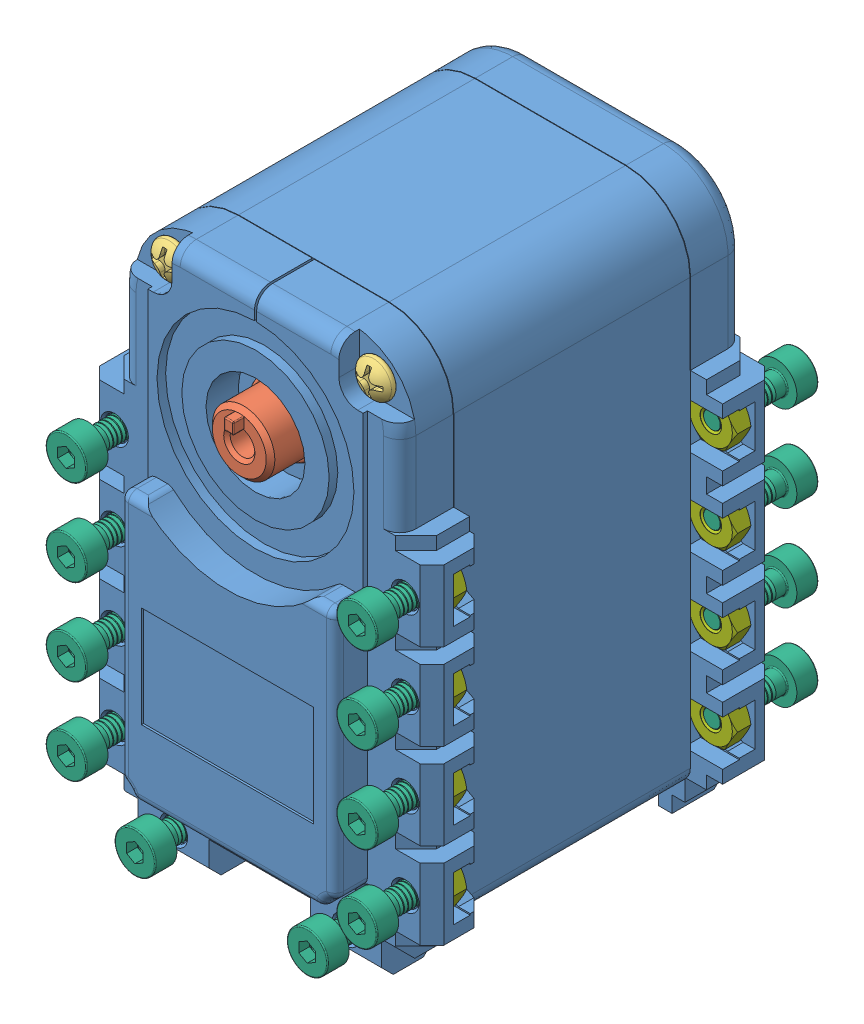
SolidWorks assembly AX-18F, configuration Défaut. Lengths in mm.
Overall size (32 50.04 41).
49 component instances, 7 part files, 18 mates.
Components (placement in the parent):
- ASSY_DUMMY___-1: ASSY_DUMMY___ [Défaut] at origin size (32 50.04 38.37)
- ASSY_GEAR-WHEEL___DUMMY-1: ASSY_GEAR-WHEEL___DUMMY [Défaut] at (0 0 -2) x (-1 0 0) z (0 0 1) size (6.5 6.5 5.51)
- DX124_SCREW-COVER___-1: DX124_SCREW-COVER___ [Défaut] at (9.5 8.5 14.5) x (-1 0 0) z (0 1 0) size (3.5 30.7 3.5)
- DX124_SCREW-COVER___-2: DX124_SCREW-COVER___ [Défaut] at (-9.5 8.5 14.5) x (-1 0 0) z (0 1 0) size (3.5 30.7 3.5)
- DX124_SCREW-COVER___-3: DX124_SCREW-COVER___ [Défaut] at (10.5 -33 14.5) x (-1 0 0) z (0 1 0) size (3.5 30.7 3.5)
- DX124_SCREW-COVER___-4: DX124_SCREW-COVER___ [Défaut] at (-10.5 -33 14.5) x (-1 0 0) z (0 1 0) size (3.5 30.7 3.5)
- 099990987____-1: 099990987____ [Défaut] at (5.05 -15.19 -9.75) x (1 0 0) z (0 1 0) size (9.9 9.43 4.9)
- 099990987____-2: 099990987____ [Défaut] at (-4.95 -15.19 -9.75) x (1 0 0) z (0 1 0) size (9.9 9.43 4.9)
- DC04_B01_INSERT_M3-1: DC04_B01_INSERT_M3 [Défaut] at (0 0 -18.4) x (-1 0 0) z (0 1 0) size (4.98 7 4.98)
- socket head cap screw_iso-1: socket head cap screw_iso [ISO 4762 M2 x 6 --- 6S] at (-13.5 -6.5 20.5) x (0 0 -1) z (1 0 0) size (8 3.8 3.8)
- hex nut style 1 gradeab_iso-1: hex nut style 1 gradeab_iso [Hexagon Nut ISO - 4032 - M2 - D - S] at (-13.5 -6.5 14) x (0 1 0) z (0 0 1) size (4 4.62 1.6)
- hex nut style 1 gradeab_iso-2: hex nut style 1 gradeab_iso [Hexagon Nut ISO - 4032 - M2 - D - S] at (-13.5 -14.5 14) x (0 1 0) z (0 0 1) size (4 4.62 1.6)
- hex nut style 1 gradeab_iso-3: hex nut style 1 gradeab_iso [Hexagon Nut ISO - 4032 - M2 - D - S] at (-13.5 -22.5 14) x (0 1 0) z (0 0 1) size (4 4.62 1.6)
- socket head cap screw_iso-2: socket head cap screw_iso [ISO 4762 M2 x 6 --- 6S] at (-13.5 -14.5 20.5) x (0 0 -1) z (1 0 0) size (8 3.8 3.8)
- socket head cap screw_iso-3: socket head cap screw_iso [ISO 4762 M2 x 6 --- 6S] at (-13.5 -22.5 20.5) x (0 0 -1) z (1 0 0) size (8 3.8 3.8)
- socket head cap screw_iso-4: socket head cap screw_iso [ISO 4762 M2 x 6 --- 6S] at (-13.5 -30.5 20.5) x (0 0 -1) z (1 0 0) size (8 3.8 3.8)
- hex nut style 1 gradeab_iso-4: hex nut style 1 gradeab_iso [Hexagon Nut ISO - 4032 - M2 - D - S] at (-13.5 -30.5 14) x (0 1 0) z (0 0 1) size (4 4.62 1.6)
- hex nut style 1 gradeab_iso-5: hex nut style 1 gradeab_iso [Hexagon Nut ISO - 4032 - M2 - D - S] at (13.5 -6.5 12.4001) x (0 1 0) z (0 0 -1) size (4 4.62 1.6)
- socket head cap screw_iso-5: socket head cap screw_iso [ISO 4762 M2 x 6 --- 6S] at (13.5 -6.5 20.5) x (0 0 -1) z (1 0 0) size (8 3.8 3.8)
- hex nut style 1 gradeab_iso-6: hex nut style 1 gradeab_iso [Hexagon Nut ISO - 4032 - M2 - D - S] at (13.5 -14.5 12.4001) x (0 1 0) z (0 0 -1) size (4 4.62 1.6)
- hex nut style 1 gradeab_iso-7: hex nut style 1 gradeab_iso [Hexagon Nut ISO - 4032 - M2 - D - S] at (13.5 -22.5 12.4001) x (0 1 0) z (0 0 -1) size (4 4.62 1.6)
- socket head cap screw_iso-6: socket head cap screw_iso [ISO 4762 M2 x 6 --- 6S] at (13.5 -14.5 20.5) x (0 0 -1) z (1 0 0) size (8 3.8 3.8)
- socket head cap screw_iso-7: socket head cap screw_iso [ISO 4762 M2 x 6 --- 6S] at (13.5 -22.5 20.5) x (0 0 -1) z (1 0 0) size (8 3.8 3.8)
- socket head cap screw_iso-8: socket head cap screw_iso [ISO 4762 M2 x 6 --- 6S] at (13.5 -30.5 20.5) x (0 0 -1) z (1 0 0) size (8 3.8 3.8)
- hex nut style 1 gradeab_iso-8: hex nut style 1 gradeab_iso [Hexagon Nut ISO - 4032 - M2 - D - S] at (13.5 -30.5 12.4001) x (0 1 0) z (0 0 -1) size (4 4.62 1.6)
- socket head cap screw_iso-9: socket head cap screw_iso [ISO 4762 M2 x 6 --- 6S] at (-13.5 -6.5 -20.5) x (0 0 1) z (-1 0 0) size (8 3.8 3.8)
- hex nut style 1 gradeab_iso-9: hex nut style 1 gradeab_iso [Hexagon Nut ISO - 4032 - M2 - D - S] at (-13.5 -6.5 -12.4001) x (0 1 0) z (0 0 1) size (4 4.62 1.6)
- hex nut style 1 gradeab_iso-10: hex nut style 1 gradeab_iso [Hexagon Nut ISO - 4032 - M2 - D - S] at (-13.5 -14.5 -12.4001) x (0 1 0) z (0 0 1) size (4 4.62 1.6)
- hex nut style 1 gradeab_iso-11: hex nut style 1 gradeab_iso [Hexagon Nut ISO - 4032 - M2 - D - S] at (-13.5 -22.5 -12.4001) x (0 1 0) z (0 0 1) size (4 4.62 1.6)
- socket head cap screw_iso-10: socket head cap screw_iso [ISO 4762 M2 x 6 --- 6S] at (-13.5 -14.5 -20.5) x (0 0 1) z (-1 0 0) size (8 3.8 3.8)
- socket head cap screw_iso-11: socket head cap screw_iso [ISO 4762 M2 x 6 --- 6S] at (-13.5 -22.5 -20.5) x (0 0 1) z (-1 0 0) size (8 3.8 3.8)
- socket head cap screw_iso-12: socket head cap screw_iso [ISO 4762 M2 x 6 --- 6S] at (-13.5 -30.5 -20.5) x (0 0 1) z (-1 0 0) size (8 3.8 3.8)
- hex nut style 1 gradeab_iso-12: hex nut style 1 gradeab_iso [Hexagon Nut ISO - 4032 - M2 - D - S] at (-13.5 -30.5 -12.4001) x (0 1 0) z (0 0 1) size (4 4.62 1.6)
- hex nut style 1 gradeab_iso-13: hex nut style 1 gradeab_iso [Hexagon Nut ISO - 4032 - M2 - D - S] at (13.5 -6.5 -14) x (0 1 0) z (0 0 -1) size (4 4.62 1.6)
- socket head cap screw_iso-13: socket head cap screw_iso [ISO 4762 M2 x 6 --- 6S] at (13.5 -6.5 -20.5) x (0 0 1) z (-1 0 0) size (8 3.8 3.8)
- hex nut style 1 gradeab_iso-14: hex nut style 1 gradeab_iso [Hexagon Nut ISO - 4032 - M2 - D - S] at (13.5 -14.5 -14) x (0 1 0) z (0 0 -1) size (4 4.62 1.6)
- hex nut style 1 gradeab_iso-15: hex nut style 1 gradeab_iso [Hexagon Nut ISO - 4032 - M2 - D - S] at (13.5 -22.5 -14) x (0 1 0) z (0 0 -1) size (4 4.62 1.6)
- socket head cap screw_iso-14: socket head cap screw_iso [ISO 4762 M2 x 6 --- 6S] at (13.5 -14.5 -20.5) x (0 0 1) z (-1 0 0) size (8 3.8 3.8)
- socket head cap screw_iso-15: socket head cap screw_iso [ISO 4762 M2 x 6 --- 6S] at (13.5 -22.5 -20.5) x (0 0 1) z (-1 0 0) size (8 3.8 3.8)
- socket head cap screw_iso-16: socket head cap screw_iso [ISO 4762 M2 x 6 --- 6S] at (13.5 -30.5 -20.5) x (0 0 1) z (-1 0 0) size (8 3.8 3.8)
- hex nut style 1 gradeab_iso-16: hex nut style 1 gradeab_iso [Hexagon Nut ISO - 4032 - M2 - D - S] at (13.5 -30.5 -14) x (0 1 0) z (0 0 -1) size (4 4.62 1.6)
- socket head cap screw_iso-17: socket head cap screw_iso [ISO 4762 M2 x 5 --- 5S] at (-8 -36 19.6) x (0 0 -1) z (1 0 0) size (7 3.8 3.8)
- hex nut style 1 gradeab_iso-17: hex nut style 1 gradeab_iso [Hexagon Nut ISO - 4032 - M2 - D - S] at (-8 -36 14) x (-1 0 0) z (0 0 1) size (4 4.62 1.6)
- hex nut style 1 gradeab_iso-18: hex nut style 1 gradeab_iso [Hexagon Nut ISO - 4032 - M2 - D - S] at (8 -36 14) x (-1 0 0) z (0 0 1) size (4 4.62 1.6)
- socket head cap screw_iso-18: socket head cap screw_iso [ISO 4762 M2 x 5 --- 5S] at (8 -36 19.6) x (0 0 -1) z (1 0 0) size (7 3.8 3.8)
- socket head cap screw_iso-19: socket head cap screw_iso [ISO 4762 M2 x 5 --- 5S] at (-8 -36 -19.6) x (0 0 1) z (-1 0 0) size (7 3.8 3.8)
- hex nut style 1 gradeab_iso-19: hex nut style 1 gradeab_iso [Hexagon Nut ISO - 4032 - M2 - D - S] at (-8 -36 -12.4001) x (-1 0 0) z (0 0 1) size (4 4.62 1.6)
- hex nut style 1 gradeab_iso-20: hex nut style 1 gradeab_iso [Hexagon Nut ISO - 4032 - M2 - D - S] at (8 -36 -12.4001) x (-1 0 0) z (0 0 1) size (4 4.62 1.6)
- socket head cap screw_iso-20: socket head cap screw_iso [ISO 4762 M2 x 5 --- 5S] at (8 -36 -19.6) x (0 0 1) z (-1 0 0) size (7 3.8 3.8)
Mates (geometry in assembly coordinates):
- Coaxiale1: concentric anti-aligned: cylinder of ASSY_DUMMY___-1 through (-13.5 -6.5 16) axis (0 0 -1) radius 1.1; cylinder of socket head cap screw_iso-1 through (-13.5 -6.5 52.25) axis (0 0 1) radius 1
- Distance1: distance = 2.5 mm anti-aligned: plane of ASSY_DUMMY___-1 through (0 0 16) normal (0 0 1); plane of socket head cap screw_iso-1 through (-13.5 -4.6 18.5) normal (0 0 -1)
- Coaxiale2: concentric aligned: cylinder of socket head cap screw_iso-1 through (-13.5 -6.5 52.25) axis (0 0 1) radius 1; cylinder of hex nut style 1 gradeab_iso-1 through (-13.5 -6.5 12.4) axis (0 0 1) radius 0.8
- Angle1: planar angle = 0.523599 rad aligned: plane of hex nut style 1 gradeab_iso-1 through (-15.8094 -6.5 12.4) normal (-0.866025 -0.5 0); plane of ASSY_DUMMY___-1 through (-16 -35 16) normal (-1 0 0)
- Coïncidente3: coincident anti-aligned: plane of ASSY_DUMMY___-1 through (0 0 14) normal (0 0 -1); plane of hex nut style 1 gradeab_iso-1 through (-15.8094 -6.5 14) normal (0 0 1)
- Coaxiale3: concentric aligned: cylinder of socket head cap screw_iso-17 through (-8 -36 51.35) axis (0 0 1) radius 1; cylinder of hex nut style 1 gradeab_iso-17 through (-8 -36 12.4) axis (0 0 1) radius 0.8
- Coaxiale4: concentric anti-aligned: cylinder of ASSY_DUMMY___-1 through (-8 -36 16) axis (0 0 -1) radius 1.1; cylinder of socket head cap screw_iso-17 through (-8 -36 51.35) axis (0 0 1) radius 1
- Distance2: distance = 1.6 mm anti-aligned: plane of ASSY_DUMMY___-1 through (0 0 16) normal (0 0 1); plane of socket head cap screw_iso-17 through (-8 -34.1 17.6) normal (0 0 -1)
- Angle2: planar angle = 0.523599 rad aligned: plane of hex nut style 1 gradeab_iso-17 through (-8 -38.3094 12.4) normal (0.5 -0.866025 0); plane of ASSY_DUMMY___-1 through (12.5 -38.5 16) normal (0 -1 0)
- Coïncidente4: coincident anti-aligned: plane of ASSY_DUMMY___-1 through (0 0 14) normal (0 0 -1); plane of hex nut style 1 gradeab_iso-17 through (-8 -38.3094 14) normal (0 0 1)
- Coaxiale13: concentric anti-aligned: cylinder of ASSY_DUMMY___-1 through (-13.5 -6.5 -16) axis (0 0 1) radius 1.1; cylinder of ? through (-13.5 -6.5 -52.75) axis (0 0 -1) radius 1
- Distance7: distance = 3 mm anti-aligned: plane of ASSY_DUMMY___-1 through (0 0 -16) normal (0 0 -1); plane of ? through (-13.5 -4.6 -19) normal (0 0 1)
- Coaxiale14: concentric anti-aligned: cylinder of ? through (-13.5 -6.5 -52.75) axis (0 0 -1) radius 1; cylinder of hex nut style 1 gradeab_iso-9 through (-13.5 -6.5 -14.0001) axis (0 0 1) radius 0.8
- Angle7: planar angle = 0.523599 rad aligned: plane of hex nut style 1 gradeab_iso-9 through (-15.8094 -6.5 -14.0001) normal (-0.866025 -0.5 0); plane of ASSY_DUMMY___-1 through (-16 -35 -16) normal (-1 0 0)
- Coaxiale15: concentric anti-aligned: cylinder of ? through (-8 -36 -52.75) axis (0 0 -1) radius 1; cylinder of hex nut style 1 gradeab_iso-19 through (-8 -36 -14.0001) axis (0 0 1) radius 0.8
- Coaxiale16: concentric anti-aligned: cylinder of ASSY_DUMMY___-1 through (-8 -36 -16) axis (0 0 1) radius 1.1; cylinder of ? through (-8 -36 -52.75) axis (0 0 -1) radius 1
- Distance8: distance = 3 mm anti-aligned: plane of ASSY_DUMMY___-1 through (0 0 -16) normal (0 0 -1); plane of ? through (-8 -34.1 -19) normal (0 0 1)
- Angle8: planar angle = 0.523599 rad aligned: plane of hex nut style 1 gradeab_iso-19 through (-8 -38.3094 -14.0001) normal (0.5 -0.866025 0); plane of ASSY_DUMMY___-1 through (12.5 -38.5 -16) normal (0 -1 0)
